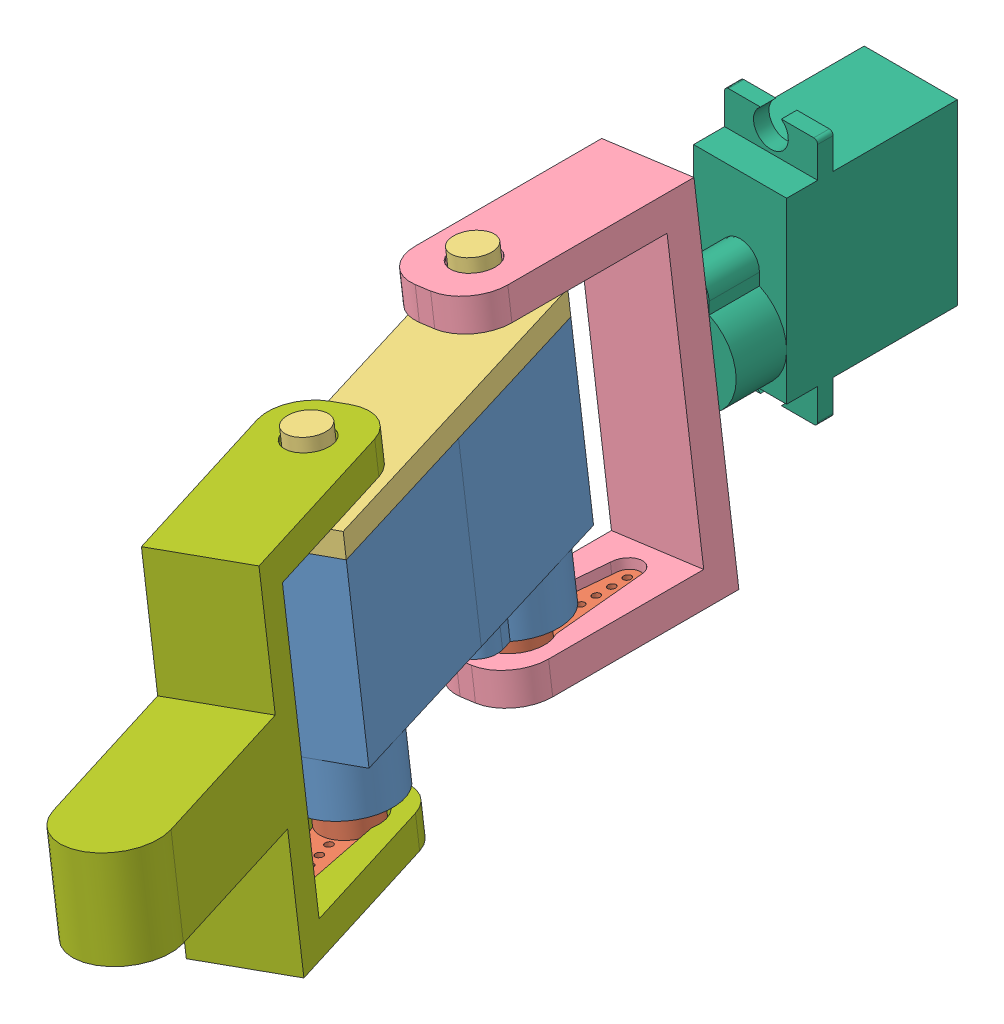
SolidWorks assembly PROSTHETIC LEG, configuration Default. Lengths in mm.
Overall size (46.13 48.29 134.82).
9 component instances, 7 part files, 23 mates.
Components (placement in the parent):
- SERVO SG90 NO_MOUNT-2: SERVO SG90 NO_MOUNT [Default] at (-1.6181 18.3461 195.9658) x (0.93877 0.126038 -0.320665) z (-0.317813 -0.042669 -0.947193) size (12 32 23)
- SERVO SG90 HORN1-4: SERVO SG90 HORN1 [Default] at (8.6946 -14.0699 53.3908) x (0 0 -1) z (0.991107 0.133065 0) size (19.3 4 6.9)
- SERVO SG90 NO_MOUNT-3: SERVO SG90 NO_MOUNT [Default] at (20.8976 21.369 -56.9796) x (-0.93877 -0.126038 0.320665) z (0.317813 0.042669 0.947193) size (12 32 23)
- SERVO SG90 HORN1-5: SERVO SG90 HORN1 [Default] at (19.5002 -12.6192 85.5954) x (0.32268 0.043323 0.945516) z (-0.937108 -0.125815 0.325575) size (19.3 4 6.9)
- Legopiece-2: Legopiece [Default] at (9.4346 19.83 69.4118) x (-0.93877 -0.126038 0.320665) z (-0.317813 -0.042669 -0.947193) size (12 10 46)
- Legopiece2-2: Legopiece2 [Default] at (8.3619 -11.5922 53.3908) x (0 0 -1) z (0.991107 0.133065 0) size (29 43.5 12)
- SERVO SG90 HORN2-1: SERVO SG90 HORN2 [Default] at (6 6 33.5) x (-0.116861 0.993148 0) z (-0.993148 -0.116861 0) size (31.7 4 6.9)
- SERVO SG90 MOUNT-2: SERVO SG90 MOUNT [Default] at (57.3144 -93.1516 0) x (-1 0 0) z (0 1 0) size (12 32 32)
- Legopiece3-1: Legopiece3 [Default] at (19.1675 -10.1414 85.5954) x (0.323454 0.043426 0.945247) z (-0.936841 -0.125779 0.326357) size (56.61 43.5 12)
Mates (geometry in assembly coordinates):
- Coincident8: coincident aligned: plane of SERVO SG90 NO_MOUNT-2 through (14.2442 -1.7217 93.2025) normal (-0.93877 -0.126038 0.320665); plane of SERVO SG90 NO_MOUNT-3 through (-0.3752 -3.6844 49.6316) normal (-0.93877 -0.126038 0.320665)
- Coincident9: coincident anti-aligned: plane of SERVO SG90 HORN1-4 through (8.495 -12.5833 53.3908) normal (-0.133065 0.991107 0); plane of SERVO SG90 NO_MOUNT-3 through (8.495 -12.5833 53.3908) normal (0.133065 -0.991107 0)
- Concentric2: concentric aligned: cylinder of SERVO SG90 HORN1-4 through (8.5615 -13.0788 53.3908) axis (-0.133065 0.991107 0) radius 1.275; cylinder of SERVO SG90 NO_MOUNT-3 through (8.495 -12.5833 53.3908) axis (-0.133065 0.991107 0) radius 2.5
- Coincident10: coincident anti-aligned: plane of SERVO SG90 NO_MOUNT-2 through (19.3006 -11.1325 85.5954) normal (0.133065 -0.991107 0); plane of SERVO SG90 HORN1-5 through (19.3006 -11.1325 85.5954) normal (-0.133065 0.991107 0)
- Concentric4: concentric aligned: cylinder of SERVO SG90 NO_MOUNT-2 through (19.3006 -11.1325 85.5954) axis (-0.133065 0.991107 0) radius 2.5; cylinder of SERVO SG90 HORN1-5 through (19.3671 -11.6281 85.5954) axis (-0.133065 0.991107 0) radius 1.275
- Coincident13: coincident anti-aligned: plane of SERVO SG90 NO_MOUNT-2 through (15.0425 20.5829 85.5954) normal (-0.133065 0.991107 0); plane of Legopiece-2 through (15.0425 20.5829 85.5954) normal (0.133065 -0.991107 0)
- Coincident14: coincident aligned: plane of SERVO SG90 NO_MOUNT-2 through (14.2442 -1.7217 93.2025) normal (-0.93877 -0.126038 0.320665); plane of Legopiece-2 through (-3.7018 21.0933 49.6316) normal (-0.93877 -0.126038 0.320665)
- Coincident15: coincident aligned: plane of SERVO SG90 NO_MOUNT-2 through (14.2442 -1.7217 93.2025) normal (0.317813 0.042669 0.947193); plane of Legopiece-2 through (22.1828 24.5685 89.3545) normal (0.317813 0.042669 0.947193)
- Coincident16: coincident anti-aligned: plane of SERVO SG90 HORN1-4 through (8.6946 -14.0699 39.0408) normal (0.133065 -0.991107 0); plane of Legopiece2-2 through (8.6946 -14.0699 39.1367) normal (-0.133065 0.991107 0)
- Concentric5: concentric anti-aligned: cylinder of SERVO SG90 HORN1-4 through (8.495 -12.5833 53.3908) axis (0.133065 -0.991107 0) radius 3.45; cylinder of Legopiece2-2 through (8.6946 -14.0699 53.3908) axis (-0.133065 0.991107 0) radius 3.8737
- Coincident20: coincident anti-aligned: plane of SERVO SG90 NO_MOUNT-3 through (4.2369 19.1322 53.3908) normal (-0.133065 0.991107 0); plane of Legopiece-2 through (15.0425 20.5829 85.5954) normal (0.133065 -0.991107 0)
- Coincident21: coincident anti-aligned: plane of SERVO SG90 NO_MOUNT-2 through (6.9345 -2.703 71.4171) normal (-0.317813 -0.042669 -0.947193); plane of SERVO SG90 NO_MOUNT-3 through (18.1998 -1.1906 67.5691) normal (0.317813 0.042669 0.947193)
- Coincident22: coincident anti-aligned: plane of SERVO SG90 HORN2-1 through (6 6 32) normal (0 0 -1); plane of SERVO SG90 MOUNT-2 through (6 6 32) normal (0 0 1)
- Concentric7: concentric anti-aligned: cylinder of SERVO SG90 HORN2-1 through (6 6 29.5) axis (0 0 1) radius 2.35; cylinder of SERVO SG90 MOUNT-2 through (6 6 32) axis (0 0 -1) radius 2.5
- Coincident23: coincident anti-aligned: plane of Legopiece2-2 through (4.0801 20.2932 33.5) normal (0 0 -1); plane of SERVO SG90 HORN2-1 through (4.3231 20.2517 33.5) normal (0 0 1)
- Concentric8: concentric anti-aligned: cylinder of Legopiece2-2 through (6 6 33.5) axis (0 0 -1) radius 4.3115; cylinder of SERVO SG90 HORN2-1 through (6 6 32) axis (0 0 1) radius 2.35
- Coincident24: coincident anti-aligned: plane of SERVO SG90 MOUNT-2 through (6 6 0) normal (0 0 -1)
- Coincident25: coincident anti-aligned: plane of SERVO SG90 MOUNT-2 through (0 0 22) normal (-1 0 0)
- Coincident26: coincident anti-aligned: plane of SERVO SG90 MOUNT-2 through (12 0 22) normal (0 -1 0)
- Parallel3: parallel anti-aligned: plane of Legopiece2-2 through (9.991 4.3689 33.5) normal (-0.999973 -0.007341 0); plane of SERVO SG90 HORN2-1 through (9.0748 4.4354 32) normal (0.999973 0.007341 0)
- Concentric9: concentric anti-aligned: cylinder of SERVO SG90 HORN1-5 through (19.3006 -11.1325 85.5954) axis (0.133065 -0.991107 0) radius 3.45; cylinder of Legopiece3-1 through (19.5002 -12.6192 85.5954) axis (-0.133065 0.991107 0) radius 3.8737
- Coincident27: coincident anti-aligned: plane of SERVO SG90 HORN1-5 through (24.1307 -11.9975 99.1635) normal (0.133065 -0.991107 0); plane of Legopiece3-1 through (24.1108 -12.0002 99.069) normal (-0.133065 0.991107 0)
- Parallel4: parallel anti-aligned: plane of SERVO SG90 HORN1-5 through (17.2276 -11.4108 88.339) normal (-0.896111 -0.12031 0.427213); plane of Legopiece3-1 through (22.2723 -12.247 99.7095) normal (0.896111 0.12031 -0.427213)
